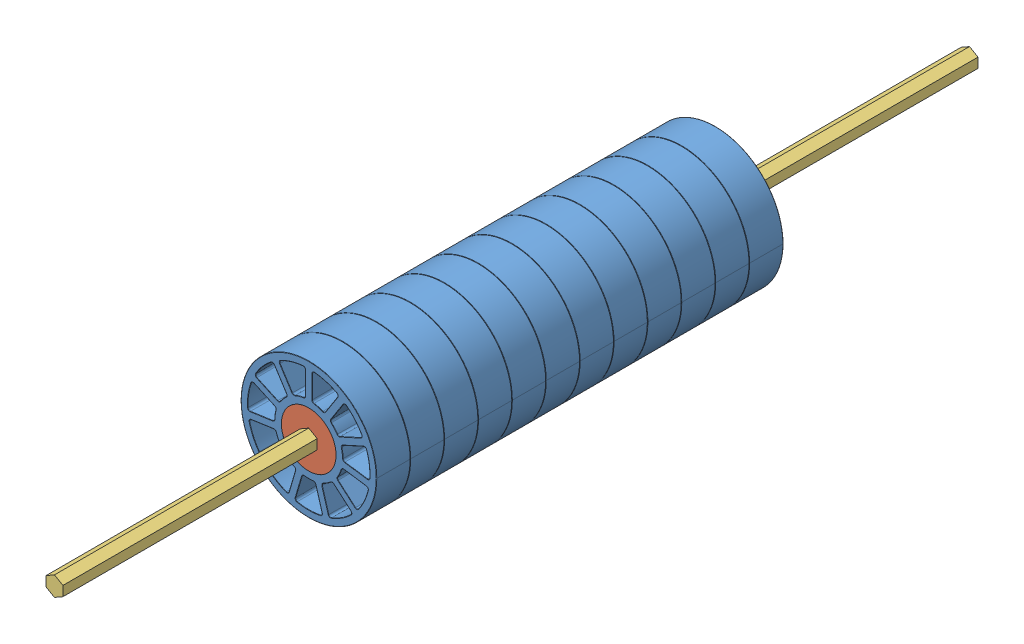
SolidWorks assembly FRC2020_Intake_Roller_v1, configuration Default. Lengths in mm.
Overall size (101.6 101.6 685.8).
49 component instances, 3 part files, 26 mates.
Components (placement in the parent):
- am-3480 4IN 500Hex Compliant Wheel REV2-1: am-3480 4IN 500Hex Compliant Wheel REV2 [Default] at (-77.5239 23.9798 24.6166) size (101.6 101.6 25.4)
  - am-3480 4IN 500Hex Compliant Wheel REV2.STEP-1: am-3480 4IN 500Hex Compliant Wheel REV2.STEP [Default] at origin size (101.6 101.6 25.4)
    - 4IN Compliant Wheel FINAL Overmold.STEP-1: 4IN Compliant Wheel FINAL Overmold.STEP [Default] at (-16.2374 3.8509 18.652) size (101.6 101.6 25.4)
    - 2in Wheel Intergrated 0500 HEX Hub.STEP-1: 2in Wheel Intergrated 0500 HEX Hub.STEP [Default] at (-16.2374 3.8509 5.952) x (-1 0 0) z (0 0 -1) size (41.91 41.91 25.4)
- am-3480 4IN 500Hex Compliant Wheel REV2-2: am-3480 4IN 500Hex Compliant Wheel REV2 [Default] at (-77.5239 23.9798 -51.5834) size (101.6 101.6 25.4)
  - am-3480 4IN 500Hex Compliant Wheel REV2.STEP-1: am-3480 4IN 500Hex Compliant Wheel REV2.STEP [Default] at origin size (101.6 101.6 25.4)
    - 4IN Compliant Wheel FINAL Overmold.STEP-1: 4IN Compliant Wheel FINAL Overmold.STEP [Default] at (-16.2374 3.8509 18.652) size (101.6 101.6 25.4)
    - 2in Wheel Intergrated 0500 HEX Hub.STEP-1: 2in Wheel Intergrated 0500 HEX Hub.STEP [Default] at (-16.2374 3.8509 5.952) x (-1 0 0) z (0 0 -1) size (41.91 41.91 25.4)
- am-3480 4IN 500Hex Compliant Wheel REV2-3: am-3480 4IN 500Hex Compliant Wheel REV2 [Default] at (-77.5239 23.9798 -26.1834) size (101.6 101.6 25.4)
  - am-3480 4IN 500Hex Compliant Wheel REV2.STEP-1: am-3480 4IN 500Hex Compliant Wheel REV2.STEP [Default] at origin size (101.6 101.6 25.4)
    - 4IN Compliant Wheel FINAL Overmold.STEP-1: 4IN Compliant Wheel FINAL Overmold.STEP [Default] at (-16.2374 3.8509 18.652) size (101.6 101.6 25.4)
    - 2in Wheel Intergrated 0500 HEX Hub.STEP-1: 2in Wheel Intergrated 0500 HEX Hub.STEP [Default] at (-16.2374 3.8509 5.952) x (-1 0 0) z (0 0 -1) size (41.91 41.91 25.4)
- am-3480 4IN 500Hex Compliant Wheel REV2-4: am-3480 4IN 500Hex Compliant Wheel REV2 [Default] at (-77.5239 23.9798 177.0166) size (101.6 101.6 25.4)
  - am-3480 4IN 500Hex Compliant Wheel REV2.STEP-1: am-3480 4IN 500Hex Compliant Wheel REV2.STEP [Default] at origin size (101.6 101.6 25.4)
    - 4IN Compliant Wheel FINAL Overmold.STEP-1: 4IN Compliant Wheel FINAL Overmold.STEP [Default] at (-16.2374 3.8509 18.652) size (101.6 101.6 25.4)
    - 2in Wheel Intergrated 0500 HEX Hub.STEP-1: 2in Wheel Intergrated 0500 HEX Hub.STEP [Default] at (-16.2374 3.8509 5.952) x (-1 0 0) z (0 0 -1) size (41.91 41.91 25.4)
- am-3480 4IN 500Hex Compliant Wheel REV2-5: am-3480 4IN 500Hex Compliant Wheel REV2 [Default] at (-77.5239 23.9798 151.6166) size (101.6 101.6 25.4)
  - am-3480 4IN 500Hex Compliant Wheel REV2.STEP-1: am-3480 4IN 500Hex Compliant Wheel REV2.STEP [Default] at origin size (101.6 101.6 25.4)
    - 4IN Compliant Wheel FINAL Overmold.STEP-1: 4IN Compliant Wheel FINAL Overmold.STEP [Default] at (-16.2374 3.8509 18.652) size (101.6 101.6 25.4)
    - 2in Wheel Intergrated 0500 HEX Hub.STEP-1: 2in Wheel Intergrated 0500 HEX Hub.STEP [Default] at (-16.2374 3.8509 5.952) x (-1 0 0) z (0 0 -1) size (41.91 41.91 25.4)
- am-3480 4IN 500Hex Compliant Wheel REV2-6: am-3480 4IN 500Hex Compliant Wheel REV2 [Default] at (-77.5239 23.9798 202.4166) size (101.6 101.6 25.4)
  - am-3480 4IN 500Hex Compliant Wheel REV2.STEP-1: am-3480 4IN 500Hex Compliant Wheel REV2.STEP [Default] at origin size (101.6 101.6 25.4)
    - 4IN Compliant Wheel FINAL Overmold.STEP-1: 4IN Compliant Wheel FINAL Overmold.STEP [Default] at (-16.2374 3.8509 18.652) size (101.6 101.6 25.4)
    - 2in Wheel Intergrated 0500 HEX Hub.STEP-1: 2in Wheel Intergrated 0500 HEX Hub.STEP [Default] at (-16.2374 3.8509 5.952) x (-1 0 0) z (0 0 -1) size (41.91 41.91 25.4)
- am-3480 4IN 500Hex Compliant Wheel REV2-7: am-3480 4IN 500Hex Compliant Wheel REV2 [Default] at (-77.5239 23.9798 100.8166) size (101.6 101.6 25.4)
  - am-3480 4IN 500Hex Compliant Wheel REV2.STEP-1: am-3480 4IN 500Hex Compliant Wheel REV2.STEP [Default] at origin size (101.6 101.6 25.4)
    - 4IN Compliant Wheel FINAL Overmold.STEP-1: 4IN Compliant Wheel FINAL Overmold.STEP [Default] at (-16.2374 3.8509 18.652) size (101.6 101.6 25.4)
    - 2in Wheel Intergrated 0500 HEX Hub.STEP-1: 2in Wheel Intergrated 0500 HEX Hub.STEP [Default] at (-16.2374 3.8509 5.952) x (-1 0 0) z (0 0 -1) size (41.91 41.91 25.4)
- am-3480 4IN 500Hex Compliant Wheel REV2-8: am-3480 4IN 500Hex Compliant Wheel REV2 [Default] at (-77.5239 23.9798 126.2166) size (101.6 101.6 25.4)
  - am-3480 4IN 500Hex Compliant Wheel REV2.STEP-1: am-3480 4IN 500Hex Compliant Wheel REV2.STEP [Default] at origin size (101.6 101.6 25.4)
    - 4IN Compliant Wheel FINAL Overmold.STEP-1: 4IN Compliant Wheel FINAL Overmold.STEP [Default] at (-16.2374 3.8509 18.652) size (101.6 101.6 25.4)
    - 2in Wheel Intergrated 0500 HEX Hub.STEP-1: 2in Wheel Intergrated 0500 HEX Hub.STEP [Default] at (-16.2374 3.8509 5.952) x (-1 0 0) z (0 0 -1) size (41.91 41.91 25.4)
- am-3480 4IN 500Hex Compliant Wheel REV2-9: am-3480 4IN 500Hex Compliant Wheel REV2 [Default] at (-109.9987 23.9798 239.7207) x (-1 0 0) z (0 0 -1) size (101.6 101.6 25.4)
  - am-3480 4IN 500Hex Compliant Wheel REV2.STEP-1: am-3480 4IN 500Hex Compliant Wheel REV2.STEP [Default] at origin size (101.6 101.6 25.4)
    - 4IN Compliant Wheel FINAL Overmold.STEP-1: 4IN Compliant Wheel FINAL Overmold.STEP [Default] at (-16.2374 3.8509 18.652) size (101.6 101.6 25.4)
    - 2in Wheel Intergrated 0500 HEX Hub.STEP-1: 2in Wheel Intergrated 0500 HEX Hub.STEP [Default] at (-16.2374 3.8509 5.952) x (-1 0 0) z (0 0 -1) size (41.91 41.91 25.4)
- am-3480 4IN 500Hex Compliant Wheel REV2-10: am-3480 4IN 500Hex Compliant Wheel REV2 [Default] at (-77.5239 23.9798 50.0166) size (101.6 101.6 25.4)
  - am-3480 4IN 500Hex Compliant Wheel REV2.STEP-1: am-3480 4IN 500Hex Compliant Wheel REV2.STEP [Default] at origin size (101.6 101.6 25.4)
    - 4IN Compliant Wheel FINAL Overmold.STEP-1: 4IN Compliant Wheel FINAL Overmold.STEP [Default] at (-16.2374 3.8509 18.652) size (101.6 101.6 25.4)
    - 2in Wheel Intergrated 0500 HEX Hub.STEP-1: 2in Wheel Intergrated 0500 HEX Hub.STEP [Default] at (-16.2374 3.8509 5.952) x (-1 0 0) z (0 0 -1) size (41.91 41.91 25.4)
- am-3480 4IN 500Hex Compliant Wheel REV2-11: am-3480 4IN 500Hex Compliant Wheel REV2 [Default] at (-77.5239 23.9798 -0.7834) size (101.6 101.6 25.4)
  - am-3480 4IN 500Hex Compliant Wheel REV2.STEP-1: am-3480 4IN 500Hex Compliant Wheel REV2.STEP [Default] at origin size (101.6 101.6 25.4)
    - 4IN Compliant Wheel FINAL Overmold.STEP-1: 4IN Compliant Wheel FINAL Overmold.STEP [Default] at (-16.2374 3.8509 18.652) size (101.6 101.6 25.4)
    - 2in Wheel Intergrated 0500 HEX Hub.STEP-1: 2in Wheel Intergrated 0500 HEX Hub.STEP [Default] at (-16.2374 3.8509 5.952) x (-1 0 0) z (0 0 -1) size (41.91 41.91 25.4)
- am-3480 4IN 500Hex Compliant Wheel REV2-12: am-3480 4IN 500Hex Compliant Wheel REV2 [Default] at (-77.5239 23.9798 75.4166) size (101.6 101.6 25.4)
  - am-3480 4IN 500Hex Compliant Wheel REV2.STEP-1: am-3480 4IN 500Hex Compliant Wheel REV2.STEP [Default] at origin size (101.6 101.6 25.4)
    - 4IN Compliant Wheel FINAL Overmold.STEP-1: 4IN Compliant Wheel FINAL Overmold.STEP [Default] at (-16.2374 3.8509 18.652) size (101.6 101.6 25.4)
    - 2in Wheel Intergrated 0500 HEX Hub.STEP-1: 2in Wheel Intergrated 0500 HEX Hub.STEP [Default] at (-16.2374 3.8509 5.952) x (-1 0 0) z (0 0 -1) size (41.91 41.91 25.4)
- FRC2020_Hex_Shaft_27in_v1-1: FRC2020_Hex_Shaft_27in_v1 [Default] at (-98.0482 31.5767 -248.8313) x (-0.977721 -0.209909 0) z (-0.209909 0.977721 0) size (13.96 685.8 14.34)
Mates (geometry in assembly coordinates):
- Coincident14: coincident aligned: line of am-3480 4IN 500Hex Compliant Wheel REV2-2/am-3480 4IN 500Hex Compliant Wheel REV2.STEP-1/2in Wheel Intergrated 0500 HEX Hub.STEP-1 through (-100.1367 31.5116 -32.9313) axis (0 -1 0); line of am-3480 4IN 500Hex Compliant Wheel REV2-3/am-3480 4IN 500Hex Compliant Wheel REV2.STEP-1/2in Wheel Intergrated 0500 HEX Hub.STEP-1 through (-100.1367 31.5116 -32.9313) axis (0 -1 0)
- Coincident16: coincident aligned: line of am-3480 4IN 500Hex Compliant Wheel REV2-2/am-3480 4IN 500Hex Compliant Wheel REV2.STEP-1/2in Wheel Intergrated 0500 HEX Hub.STEP-1 through (-87.3859 31.5116 -32.9313) axis (-0.866025 0.5 0); line of am-3480 4IN 500Hex Compliant Wheel REV2-3/am-3480 4IN 500Hex Compliant Wheel REV2.STEP-1/2in Wheel Intergrated 0500 HEX Hub.STEP-1 through (-87.3859 31.5116 -32.9313) axis (-0.866025 0.5 0)
- Coincident17: coincident aligned: line of am-3480 4IN 500Hex Compliant Wheel REV2-3/am-3480 4IN 500Hex Compliant Wheel REV2.STEP-1/2in Wheel Intergrated 0500 HEX Hub.STEP-1 through (-93.7613 35.1924 -7.5313) axis (-0.866025 -0.5 0); line of am-3480 4IN 500Hex Compliant Wheel REV2-11/am-3480 4IN 500Hex Compliant Wheel REV2.STEP-1/2in Wheel Intergrated 0500 HEX Hub.STEP-1 through (-93.7613 35.1924 -7.5313) axis (-0.866025 -0.5 0)
- Coincident18: coincident aligned: line of am-3480 4IN 500Hex Compliant Wheel REV2-3/am-3480 4IN 500Hex Compliant Wheel REV2.STEP-1/2in Wheel Intergrated 0500 HEX Hub.STEP-1 through (-87.3859 31.5116 -7.5313) axis (-0.866025 0.5 0); line of am-3480 4IN 500Hex Compliant Wheel REV2-11/am-3480 4IN 500Hex Compliant Wheel REV2.STEP-1/2in Wheel Intergrated 0500 HEX Hub.STEP-1 through (-87.3859 31.5116 -7.5313) axis (-0.866025 0.5 0)
- Coincident19: coincident aligned: line of am-3480 4IN 500Hex Compliant Wheel REV2-1/am-3480 4IN 500Hex Compliant Wheel REV2.STEP-1/2in Wheel Intergrated 0500 HEX Hub.STEP-1 through (-87.3859 31.5116 17.8687) axis (-0.866025 0.5 0); line of am-3480 4IN 500Hex Compliant Wheel REV2-11/am-3480 4IN 500Hex Compliant Wheel REV2.STEP-1/2in Wheel Intergrated 0500 HEX Hub.STEP-1 through (-87.3859 31.5116 17.8687) axis (-0.866025 0.5 0)
- Coincident20: coincident aligned: line of am-3480 4IN 500Hex Compliant Wheel REV2-1/am-3480 4IN 500Hex Compliant Wheel REV2.STEP-1/2in Wheel Intergrated 0500 HEX Hub.STEP-1 through (-87.3859 24.1499 17.8687) axis (0 1 0); line of am-3480 4IN 500Hex Compliant Wheel REV2-11/am-3480 4IN 500Hex Compliant Wheel REV2.STEP-1/2in Wheel Intergrated 0500 HEX Hub.STEP-1 through (-87.3859 24.1499 17.8687) axis (0 1 0)
- Coincident21: coincident aligned: line of am-3480 4IN 500Hex Compliant Wheel REV2-1/am-3480 4IN 500Hex Compliant Wheel REV2.STEP-1/2in Wheel Intergrated 0500 HEX Hub.STEP-1 through (-87.3859 24.1499 43.2687) axis (0 1 0); line of am-3480 4IN 500Hex Compliant Wheel REV2-10/am-3480 4IN 500Hex Compliant Wheel REV2.STEP-1/2in Wheel Intergrated 0500 HEX Hub.STEP-1 through (-87.3859 24.1499 43.2687) axis (0 1 0)
- Coincident22: coincident aligned: line of am-3480 4IN 500Hex Compliant Wheel REV2-1/am-3480 4IN 500Hex Compliant Wheel REV2.STEP-1/2in Wheel Intergrated 0500 HEX Hub.STEP-1 through (-93.7613 20.469 43.2687) axis (0.866025 0.5 0); line of am-3480 4IN 500Hex Compliant Wheel REV2-10/am-3480 4IN 500Hex Compliant Wheel REV2.STEP-1/2in Wheel Intergrated 0500 HEX Hub.STEP-1 through (-93.7613 20.469 43.2687) axis (0.866025 0.5 0)
- Coincident23: coincident aligned: line of am-3480 4IN 500Hex Compliant Wheel REV2-10/am-3480 4IN 500Hex Compliant Wheel REV2.STEP-1/2in Wheel Intergrated 0500 HEX Hub.STEP-1 through (-87.3859 24.1499 68.6687) axis (0 1 0); line of am-3480 4IN 500Hex Compliant Wheel REV2-12/am-3480 4IN 500Hex Compliant Wheel REV2.STEP-1/2in Wheel Intergrated 0500 HEX Hub.STEP-1 through (-87.3859 24.1499 68.6687) axis (0 1 0)
- Coincident24: coincident aligned: line of am-3480 4IN 500Hex Compliant Wheel REV2-10/am-3480 4IN 500Hex Compliant Wheel REV2.STEP-1/2in Wheel Intergrated 0500 HEX Hub.STEP-1 through (-93.7613 20.469 68.6687) axis (0.866025 0.5 0); line of am-3480 4IN 500Hex Compliant Wheel REV2-12/am-3480 4IN 500Hex Compliant Wheel REV2.STEP-1/2in Wheel Intergrated 0500 HEX Hub.STEP-1 through (-93.7613 20.469 68.6687) axis (0.866025 0.5 0)
- Coincident25: coincident aligned: line of am-3480 4IN 500Hex Compliant Wheel REV2-7/am-3480 4IN 500Hex Compliant Wheel REV2.STEP-1/2in Wheel Intergrated 0500 HEX Hub.STEP-1 through (-87.3859 24.1499 94.0687) axis (0 1 0); line of am-3480 4IN 500Hex Compliant Wheel REV2-12/am-3480 4IN 500Hex Compliant Wheel REV2.STEP-1/2in Wheel Intergrated 0500 HEX Hub.STEP-1 through (-87.3859 24.1499 94.0687) axis (0 1 0)
- Coincident26: coincident aligned: line of am-3480 4IN 500Hex Compliant Wheel REV2-7/am-3480 4IN 500Hex Compliant Wheel REV2.STEP-1/2in Wheel Intergrated 0500 HEX Hub.STEP-1 through (-93.7613 20.469 94.0687) axis (0.866025 0.5 0); line of am-3480 4IN 500Hex Compliant Wheel REV2-12/am-3480 4IN 500Hex Compliant Wheel REV2.STEP-1/2in Wheel Intergrated 0500 HEX Hub.STEP-1 through (-93.7613 20.469 94.0687) axis (0.866025 0.5 0)
- Coincident27: coincident aligned: line of am-3480 4IN 500Hex Compliant Wheel REV2-7/am-3480 4IN 500Hex Compliant Wheel REV2.STEP-1/2in Wheel Intergrated 0500 HEX Hub.STEP-1 through (-87.3859 24.1499 119.4687) axis (0 1 0); line of am-3480 4IN 500Hex Compliant Wheel REV2-8/am-3480 4IN 500Hex Compliant Wheel REV2.STEP-1/2in Wheel Intergrated 0500 HEX Hub.STEP-1 through (-87.3859 24.1499 119.4687) axis (0 1 0)
- Parallel1: parallel aligned: line of am-3480 4IN 500Hex Compliant Wheel REV2-7/am-3480 4IN 500Hex Compliant Wheel REV2.STEP-1/2in Wheel Intergrated 0500 HEX Hub.STEP-1 through (-93.7613 20.469 119.4687) axis (0.866025 0.5 0); line of am-3480 4IN 500Hex Compliant Wheel REV2-8/am-3480 4IN 500Hex Compliant Wheel REV2.STEP-1/2in Wheel Intergrated 0500 HEX Hub.STEP-1 through (-93.7613 20.469 144.8687) axis (0.866025 0.5 0)
- Coincident30: coincident aligned: line of am-3480 4IN 500Hex Compliant Wheel REV2-7/am-3480 4IN 500Hex Compliant Wheel REV2.STEP-1/2in Wheel Intergrated 0500 HEX Hub.STEP-1 through (-93.7613 20.469 119.4687) axis (0.866025 0.5 0); line of am-3480 4IN 500Hex Compliant Wheel REV2-8/am-3480 4IN 500Hex Compliant Wheel REV2.STEP-1/2in Wheel Intergrated 0500 HEX Hub.STEP-1 through (-93.7613 20.469 119.4687) axis (0.866025 0.5 0)
- Coincident31: coincident aligned: line of am-3480 4IN 500Hex Compliant Wheel REV2-5/am-3480 4IN 500Hex Compliant Wheel REV2.STEP-1/2in Wheel Intergrated 0500 HEX Hub.STEP-1 through (-87.3859 24.1499 144.8687) axis (0 1 0); line of am-3480 4IN 500Hex Compliant Wheel REV2-8/am-3480 4IN 500Hex Compliant Wheel REV2.STEP-1/2in Wheel Intergrated 0500 HEX Hub.STEP-1 through (-87.3859 24.1499 144.8687) axis (0 1 0)
- Coincident32: coincident aligned: line of am-3480 4IN 500Hex Compliant Wheel REV2-5/am-3480 4IN 500Hex Compliant Wheel REV2.STEP-1/2in Wheel Intergrated 0500 HEX Hub.STEP-1 through (-93.7613 20.469 144.8687) axis (0.866025 0.5 0); line of am-3480 4IN 500Hex Compliant Wheel REV2-8/am-3480 4IN 500Hex Compliant Wheel REV2.STEP-1/2in Wheel Intergrated 0500 HEX Hub.STEP-1 through (-93.7613 20.469 144.8687) axis (0.866025 0.5 0)
- Coincident33: coincident aligned: line of am-3480 4IN 500Hex Compliant Wheel REV2-4/am-3480 4IN 500Hex Compliant Wheel REV2.STEP-1/2in Wheel Intergrated 0500 HEX Hub.STEP-1 through (-87.3859 24.1499 170.2687) axis (0 1 0); line of am-3480 4IN 500Hex Compliant Wheel REV2-5/am-3480 4IN 500Hex Compliant Wheel REV2.STEP-1/2in Wheel Intergrated 0500 HEX Hub.STEP-1 through (-87.3859 24.1499 170.2687) axis (0 1 0)
- Coincident34: coincident aligned: line of am-3480 4IN 500Hex Compliant Wheel REV2-4/am-3480 4IN 500Hex Compliant Wheel REV2.STEP-1/2in Wheel Intergrated 0500 HEX Hub.STEP-1 through (-87.3859 31.5116 170.2687) axis (-0.866025 0.5 0); line of am-3480 4IN 500Hex Compliant Wheel REV2-5/am-3480 4IN 500Hex Compliant Wheel REV2.STEP-1/2in Wheel Intergrated 0500 HEX Hub.STEP-1 through (-87.3859 31.5116 170.2687) axis (-0.866025 0.5 0)
- Coincident35: coincident aligned: line of am-3480 4IN 500Hex Compliant Wheel REV2-4/am-3480 4IN 500Hex Compliant Wheel REV2.STEP-1/2in Wheel Intergrated 0500 HEX Hub.STEP-1 through (-87.3859 24.1499 195.6687) axis (0 1 0); line of am-3480 4IN 500Hex Compliant Wheel REV2-6/am-3480 4IN 500Hex Compliant Wheel REV2.STEP-1/2in Wheel Intergrated 0500 HEX Hub.STEP-1 through (-87.3859 24.1499 195.6687) axis (0 1 0)
- Coincident36: coincident aligned: line of am-3480 4IN 500Hex Compliant Wheel REV2-4/am-3480 4IN 500Hex Compliant Wheel REV2.STEP-1/2in Wheel Intergrated 0500 HEX Hub.STEP-1 through (-93.7613 20.469 195.6687) axis (0.866025 0.5 0); line of am-3480 4IN 500Hex Compliant Wheel REV2-6/am-3480 4IN 500Hex Compliant Wheel REV2.STEP-1/2in Wheel Intergrated 0500 HEX Hub.STEP-1 through (-93.7613 20.469 195.6687) axis (0.866025 0.5 0)
- Coincident39: coincident anti-aligned: line of am-3480 4IN 500Hex Compliant Wheel REV2-6/am-3480 4IN 500Hex Compliant Wheel REV2.STEP-1/2in Wheel Intergrated 0500 HEX Hub.STEP-1 through (-87.3859 24.1499 221.0687) axis (0 1 0); line of am-3480 4IN 500Hex Compliant Wheel REV2-9/am-3480 4IN 500Hex Compliant Wheel REV2.STEP-1/2in Wheel Intergrated 0500 HEX Hub.STEP-1 through (-87.3859 31.5116 221.0687) axis (0 -1 0)
- Coincident40: coincident anti-aligned: line of am-3480 4IN 500Hex Compliant Wheel REV2-6/am-3480 4IN 500Hex Compliant Wheel REV2.STEP-1/2in Wheel Intergrated 0500 HEX Hub.STEP-1 through (-93.7613 35.1924 221.0687) axis (-0.866025 -0.5 0); line of am-3480 4IN 500Hex Compliant Wheel REV2-9/am-3480 4IN 500Hex Compliant Wheel REV2.STEP-1/2in Wheel Intergrated 0500 HEX Hub.STEP-1 through (-100.1367 31.5116 221.0687) axis (0.866025 0.5 0)
- Distance1: distance = 190.5 mm aligned: plane of am-3480 4IN 500Hex Compliant Wheel REV2-9/am-3480 4IN 500Hex Compliant Wheel REV2.STEP-1/2in Wheel Intergrated 0500 HEX Hub.STEP-1 through (-93.7613 30.3707 246.4687) normal (0 0 1); plane of FRC2020_Hex_Shaft_27in_v1-1 through (-98.0482 31.5767 436.9687) normal (0 0 1)
- Coincident42: coincident anti-aligned: plane of am-3480 4IN 500Hex Compliant Wheel REV2-2/am-3480 4IN 500Hex Compliant Wheel REV2.STEP-1/2in Wheel Intergrated 0500 HEX Hub.STEP-1 through (-100.1367 24.1499 -58.3313) normal (0.5 0.866025 0); plane of FRC2020_Hex_Shaft_27in_v1-1 through (-100.1621 24.1645 436.9687) normal (-0.5 -0.866025 0)
- Coincident43: coincident anti-aligned: plane of am-3480 4IN 500Hex Compliant Wheel REV2-2/am-3480 4IN 500Hex Compliant Wheel REV2.STEP-1/2in Wheel Intergrated 0500 HEX Hub.STEP-1 through (-93.7613 35.1924 -58.3313) normal (0.5 -0.866025 0); plane of FRC2020_Hex_Shaft_27in_v1-1 through (-93.8121 35.1631 436.9687) normal (-0.5 0.866025 0)
